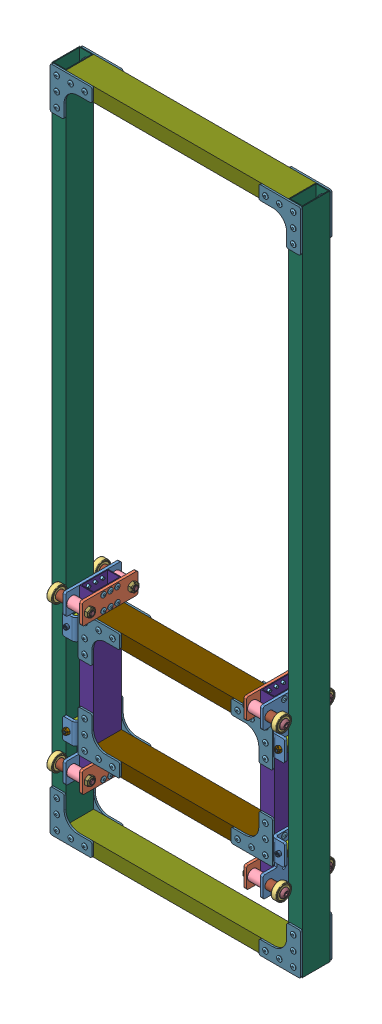
SolidWorks assembly am-3844a Example Single Stage Elevator Bearing Kit (1).STEP, configuration Default. Lengths in mm.
Overall size (457.2 1219.2 116.33).
248 component instances, 18 part files, 0 mates.
Components (placement in the parent):
- Example Single Corner Bearing Assembly R2.STEP-1: Example Single Corner Bearing Assembly R2.STEP [Default] at (14.8715 309.5253 9.4128) x (0 0 1) z (-1 0 0) size (112.43 88.9 74.91)
  - Large Bearing Block Plate R2.STEP-1: Large Bearing Block Plate R2.STEP [Default] at (-85.6128 70.3392 -35.9285) x (1 0 0) z (0 -1 0) size (101.6 24.99 88.9)
  - Small Bearing Block Plate R2.STEP-1: Small Bearing Block Plate R2.STEP [Default] at (-85.6128 70.3392 -66.091) x (1 0 0) z (0 -1 0) size (101.6 4.76 38.1)
  - 1614Z Bearing.STEP-1: 1614Z Bearing.STEP [Default] at (-74.6273 89.3892 -8.941) x (0.346238 -0.938147 0) z (0 0 1) size (28.57 28.57 9.53)
  - 1614Z Bearing.STEP-2: 1614Z Bearing.STEP [Default] at (5.0017 89.3892 -8.941) x (0.999932 0.011696 0) z (0 0 1) size (28.57 28.57 9.53)
  - AS75-18-64 Aluminum Spacer.STEP-1: AS75-18-64 Aluminum Spacer.STEP [Default] at (5.0017 89.3892 -35.9285) x (-0.078952 0.996878 0) z (-0.996878 -0.078952 0) size (19.05 25.4 19.05)
  - AS75-18-64 Aluminum Spacer.STEP-2: AS75-18-64 Aluminum Spacer.STEP [Default] at (-74.6273 89.3892 -61.3285) x (-0.205985 0.978555 0) z (0.978555 0.205985 0) size (19.05 25.4 19.05)
  - 187 pop rivet.STEP-1: 187 pop rivet.STEP [Default] at (-22.1128 102.0892 -41.707) x (0.970848 -0.239695 0) z (-0.239695 -0.970848 0) size (9.53 12.06 9.53)
  - 187 pop rivet.STEP-2: 187 pop rivet.STEP [Default] at (-22.1128 102.0892 -55.55) x (1 0 0) z (0 1 0) size (9.53 12.06 9.53)
  - 187 pop rivet.STEP-3: 187 pop rivet.STEP [Default] at (-34.8128 102.0892 -41.707) x (0.970848 -0.239695 0) z (-0.239695 -0.970848 0) size (9.53 12.06 9.53)
  - 187 pop rivet.STEP-4: 187 pop rivet.STEP [Default] at (-47.5128 102.0892 -41.707) x (0.970848 -0.239695 0) z (-0.239695 -0.970848 0) size (9.53 12.06 9.53)
  - 187 pop rivet.STEP-5: 187 pop rivet.STEP [Default] at (-22.1128 25.8892 -41.707) x (0.970848 -0.239695 0) z (-0.239695 -0.970848 0) size (9.53 12.06 9.53)
  - 187 pop rivet.STEP-6: 187 pop rivet.STEP [Default] at (-34.8128 25.8892 -41.707) x (0.970848 -0.239695 0) z (-0.239695 -0.970848 0) size (9.53 12.06 9.53)
  - 187 pop rivet.STEP-7: 187 pop rivet.STEP [Default] at (-47.5128 25.8892 -41.707) x (0.970848 -0.239695 0) z (-0.239695 -0.970848 0) size (9.53 12.06 9.53)
  - 187 pop rivet.STEP-8: 187 pop rivet.STEP [Default] at (-22.1128 76.6892 -55.55) x (1 0 0) z (0 1 0) size (9.53 12.06 9.53)
  - 187 pop rivet.STEP-9: 187 pop rivet.STEP [Default] at (-34.8128 102.0892 -55.55) x (1 0 0) z (0 1 0) size (9.53 12.06 9.53)
  - 187 pop rivet.STEP-10: 187 pop rivet.STEP [Default] at (-34.8128 76.6892 -55.55) x (1 0 0) z (0 1 0) size (9.53 12.06 9.53)
  - 187 pop rivet.STEP-11: 187 pop rivet.STEP [Default] at (-47.5128 102.0892 -55.55) x (1 0 0) z (0 1 0) size (9.53 12.06 9.53)
  - 187 pop rivet.STEP-12: 187 pop rivet.STEP [Default] at (-47.5128 76.6892 -55.55) x (1 0 0) z (0 1 0) size (9.53 12.06 9.53)
  - am-0602 .250 x .192 x 2.14 Brass Tube.STEP-1: am-0602 .250 x .192 x 2.14 Brass Tube.STEP [Default] at (-7.6348 38.5892 -20.0535) x (0 -0.358682 0.93346) z (-1 0 0) size (6.35 6.35 54.36)
  - 13RS075051 .750 x .260 x 1.00 Spacer.STEP-1: 13RS075051 .750 x .260 x 1.00 Spacer.STEP [Default] at (-60.2128 38.5892 -20.0535) x (0 -0.722855 0.691) z (0 0.691 0.722855) size (19.05 25.4 19.05)
  - 13RS075051 .750 x .260 x 1.00 Spacer.STEP-2: 13RS075051 .750 x .260 x 1.00 Spacer.STEP [Default] at (-34.8128 38.5892 -20.0535) x (0 -0.801304 -0.598258) z (0 -0.598258 0.801304) size (19.05 25.4 19.05)
  - 0.25 Flat Washer_Preferred Wide FW 0.25.STEP-1: 0.25 Flat Washer_Preferred Wide FW 0.25.STEP [Default] at (-60.2128 38.5892 -20.0535) x (1 0 0) z (0 -0.116572 0.993182) size (1.4 15.88 15.88)
  - 0.25 Flat Washer_Preferred Wide FW 0.25.STEP-2: 0.25 Flat Washer_Preferred Wide FW 0.25.STEP [Default] at (-8.0158 38.5892 -20.0535) size (1.4 15.88 15.88)
  - 10-32 Nylock Nut.STEP-1: 10-32 Nylock Nut.STEP [Default] at (-66.7533 38.5892 -20.0535) x (0 -0.097883 0.995198) z (-1 0 0) size (9.53 11.17 7.11)
  - SHCS 10-32 x 2.75_HX-SHCS 0.19-32x2.75x0.875-C.STEP-1: SHCS 10-32 x 2.75_HX-SHCS 0.19-32x2.75x0.875-C.STEP [Default] at (1.9537 38.5892 -20.0535) x (-1 0 0) z (0 -0.944703 0.327928) size (74.68 7.94 7.94)
  - AS62-18-44 Aluminum Spacer.STEP-1: AS62-18-44 Aluminum Spacer.STEP [Default] at (5.0017 89.3892 -13.7035) x (0.999229 -0.039261 0) z (0.039261 0.999229 0) size (15.88 17.46 15.88)
  - AS62-18-44 Aluminum Spacer.STEP-2: AS62-18-44 Aluminum Spacer.STEP [Default] at (-74.6273 89.3892 -13.7035) x (1 0 0) z (0 1 0) size (15.88 17.46 15.88)
  - 38-16 Nylock Jam Nut_90566A031.STEP-1: 38-16 Nylock Jam Nut_90566A031.STEP [Default] at (5.0017 89.3892 -66.091) x (1 0 0) z (0 1 0) size (14.29 6.75 16.5)
  - 38-16 Nylock Jam Nut_90566A031.STEP-2: 38-16 Nylock Jam Nut_90566A031.STEP [Default] at (-74.6273 89.3892 -66.091) x (1 0 0) z (0 1 0) size (14.29 6.75 16.5)
  - 91255A636_ALLOY STEEL BUTTON-HEAD SOCKET CAP SCREW_91255A636.STEP-1: 91255A636_ALLOY STEEL BUTTON-HEAD SOCKET CAP SCREW_91255A636.STEP [Default] at (-74.6273 89.3892 0.8761) size (16.66 16.66 74.91)
  - 91255A636_ALLOY STEEL BUTTON-HEAD SOCKET CAP SCREW_91255A636.STEP-2: 91255A636_ALLOY STEEL BUTTON-HEAD SOCKET CAP SCREW_91255A636.STEP [Default] at (5.0017 89.3892 0.8761) size (16.66 16.66 74.91)
- Example Single Corner Bearing Assembly R2.STEP-2: Example Single Corner Bearing Assembly R2.STEP [Default] at (14.8715 221.6036 -60.2128) x (0 0 -1) z (-1 0 0) size (112.43 88.9 74.91)
  - Large Bearing Block Plate R2.STEP-1: Large Bearing Block Plate R2.STEP [Default] at (-85.6128 70.3392 -35.9285) x (1 0 0) z (0 -1 0) size (101.6 24.99 88.9)
  - Small Bearing Block Plate R2.STEP-1: Small Bearing Block Plate R2.STEP [Default] at (-85.6128 70.3392 -66.091) x (1 0 0) z (0 -1 0) size (101.6 4.76 38.1)
  - 1614Z Bearing.STEP-1: 1614Z Bearing.STEP [Default] at (-74.6273 89.3892 -8.941) x (0.346238 -0.938147 0) z (0 0 1) size (28.57 28.57 9.53)
  - 1614Z Bearing.STEP-2: 1614Z Bearing.STEP [Default] at (5.0017 89.3892 -8.941) x (0.999932 0.011696 0) z (0 0 1) size (28.57 28.57 9.53)
  - AS75-18-64 Aluminum Spacer.STEP-1: AS75-18-64 Aluminum Spacer.STEP [Default] at (5.0017 89.3892 -35.9285) x (-0.078952 0.996878 0) z (-0.996878 -0.078952 0) size (19.05 25.4 19.05)
  - AS75-18-64 Aluminum Spacer.STEP-2: AS75-18-64 Aluminum Spacer.STEP [Default] at (-74.6273 89.3892 -61.3285) x (-0.205985 0.978555 0) z (0.978555 0.205985 0) size (19.05 25.4 19.05)
  - 187 pop rivet.STEP-1: 187 pop rivet.STEP [Default] at (-22.1128 102.0892 -41.707) x (0.970848 -0.239695 0) z (-0.239695 -0.970848 0) size (9.53 12.06 9.53)
  - 187 pop rivet.STEP-2: 187 pop rivet.STEP [Default] at (-22.1128 102.0892 -55.55) x (1 0 0) z (0 1 0) size (9.53 12.06 9.53)
  - 187 pop rivet.STEP-3: 187 pop rivet.STEP [Default] at (-34.8128 102.0892 -41.707) x (0.970848 -0.239695 0) z (-0.239695 -0.970848 0) size (9.53 12.06 9.53)
  - 187 pop rivet.STEP-4: 187 pop rivet.STEP [Default] at (-47.5128 102.0892 -41.707) x (0.970848 -0.239695 0) z (-0.239695 -0.970848 0) size (9.53 12.06 9.53)
  - 187 pop rivet.STEP-5: 187 pop rivet.STEP [Default] at (-22.1128 25.8892 -41.707) x (0.970848 -0.239695 0) z (-0.239695 -0.970848 0) size (9.53 12.06 9.53)
  - 187 pop rivet.STEP-6: 187 pop rivet.STEP [Default] at (-34.8128 25.8892 -41.707) x (0.970848 -0.239695 0) z (-0.239695 -0.970848 0) size (9.53 12.06 9.53)
  - 187 pop rivet.STEP-7: 187 pop rivet.STEP [Default] at (-47.5128 25.8892 -41.707) x (0.970848 -0.239695 0) z (-0.239695 -0.970848 0) size (9.53 12.06 9.53)
  - 187 pop rivet.STEP-8: 187 pop rivet.STEP [Default] at (-22.1128 76.6892 -55.55) x (1 0 0) z (0 1 0) size (9.53 12.06 9.53)
  - 187 pop rivet.STEP-9: 187 pop rivet.STEP [Default] at (-34.8128 102.0892 -55.55) x (1 0 0) z (0 1 0) size (9.53 12.06 9.53)
  - 187 pop rivet.STEP-10: 187 pop rivet.STEP [Default] at (-34.8128 76.6892 -55.55) x (1 0 0) z (0 1 0) size (9.53 12.06 9.53)
  - 187 pop rivet.STEP-11: 187 pop rivet.STEP [Default] at (-47.5128 102.0892 -55.55) x (1 0 0) z (0 1 0) size (9.53 12.06 9.53)
  - 187 pop rivet.STEP-12: 187 pop rivet.STEP [Default] at (-47.5128 76.6892 -55.55) x (1 0 0) z (0 1 0) size (9.53 12.06 9.53)
  - am-0602 .250 x .192 x 2.14 Brass Tube.STEP-1: am-0602 .250 x .192 x 2.14 Brass Tube.STEP [Default] at (-7.6348 38.5892 -20.0535) x (0 -0.358682 0.93346) z (-1 0 0) size (6.35 6.35 54.36)
  - 13RS075051 .750 x .260 x 1.00 Spacer.STEP-1: 13RS075051 .750 x .260 x 1.00 Spacer.STEP [Default] at (-60.2128 38.5892 -20.0535) x (0 -0.722855 0.691) z (0 0.691 0.722855) size (19.05 25.4 19.05)
  - 13RS075051 .750 x .260 x 1.00 Spacer.STEP-2: 13RS075051 .750 x .260 x 1.00 Spacer.STEP [Default] at (-34.8128 38.5892 -20.0535) x (0 -0.801304 -0.598258) z (0 -0.598258 0.801304) size (19.05 25.4 19.05)
  - 0.25 Flat Washer_Preferred Wide FW 0.25.STEP-1: 0.25 Flat Washer_Preferred Wide FW 0.25.STEP [Default] at (-60.2128 38.5892 -20.0535) x (1 0 0) z (0 -0.116572 0.993182) size (1.4 15.88 15.88)
  - 0.25 Flat Washer_Preferred Wide FW 0.25.STEP-2: 0.25 Flat Washer_Preferred Wide FW 0.25.STEP [Default] at (-8.0158 38.5892 -20.0535) size (1.4 15.88 15.88)
  - 10-32 Nylock Nut.STEP-1: 10-32 Nylock Nut.STEP [Default] at (-66.7533 38.5892 -20.0535) x (0 -0.097883 0.995198) z (-1 0 0) size (9.53 11.17 7.11)
  - SHCS 10-32 x 2.75_HX-SHCS 0.19-32x2.75x0.875-C.STEP-1: SHCS 10-32 x 2.75_HX-SHCS 0.19-32x2.75x0.875-C.STEP [Default] at (1.9537 38.5892 -20.0535) x (-1 0 0) z (0 -0.944703 0.327928) size (74.68 7.94 7.94)
  - AS62-18-44 Aluminum Spacer.STEP-1: AS62-18-44 Aluminum Spacer.STEP [Default] at (5.0017 89.3892 -13.7035) x (0.999229 -0.039261 0) z (0.039261 0.999229 0) size (15.88 17.46 15.88)
  - AS62-18-44 Aluminum Spacer.STEP-2: AS62-18-44 Aluminum Spacer.STEP [Default] at (-74.6273 89.3892 -13.7035) x (1 0 0) z (0 1 0) size (15.88 17.46 15.88)
  - 38-16 Nylock Jam Nut_90566A031.STEP-1: 38-16 Nylock Jam Nut_90566A031.STEP [Default] at (5.0017 89.3892 -66.091) x (1 0 0) z (0 1 0) size (14.29 6.75 16.5)
  - 38-16 Nylock Jam Nut_90566A031.STEP-2: 38-16 Nylock Jam Nut_90566A031.STEP [Default] at (-74.6273 89.3892 -66.091) x (1 0 0) z (0 1 0) size (14.29 6.75 16.5)
  - 91255A636_ALLOY STEEL BUTTON-HEAD SOCKET CAP SCREW_91255A636.STEP-1: 91255A636_ALLOY STEEL BUTTON-HEAD SOCKET CAP SCREW_91255A636.STEP [Default] at (-74.6273 89.3892 0.8761) size (16.66 16.66 74.91)
  - 91255A636_ALLOY STEEL BUTTON-HEAD SOCKET CAP SCREW_91255A636.STEP-2: 91255A636_ALLOY STEEL BUTTON-HEAD SOCKET CAP SCREW_91255A636.STEP [Default] at (5.0017 89.3892 0.8761) size (16.66 16.66 74.91)
- Example Single Corner Bearing Assembly R2.STEP-3: Example Single Corner Bearing Assembly R2.STEP [Default] at (442.3285 309.5253 -60.2128) x (0 0 -1) z (1 0 0) size (112.43 88.9 74.91)
  - Large Bearing Block Plate R2.STEP-1: Large Bearing Block Plate R2.STEP [Default] at (-85.6128 70.3392 -35.9285) x (1 0 0) z (0 -1 0) size (101.6 24.99 88.9)
  - Small Bearing Block Plate R2.STEP-1: Small Bearing Block Plate R2.STEP [Default] at (-85.6128 70.3392 -66.091) x (1 0 0) z (0 -1 0) size (101.6 4.76 38.1)
  - 1614Z Bearing.STEP-1: 1614Z Bearing.STEP [Default] at (-74.6273 89.3892 -8.941) x (0.346238 -0.938147 0) z (0 0 1) size (28.57 28.57 9.53)
  - 1614Z Bearing.STEP-2: 1614Z Bearing.STEP [Default] at (5.0017 89.3892 -8.941) x (0.999932 0.011696 0) z (0 0 1) size (28.57 28.57 9.53)
  - AS75-18-64 Aluminum Spacer.STEP-1: AS75-18-64 Aluminum Spacer.STEP [Default] at (5.0017 89.3892 -35.9285) x (-0.078952 0.996878 0) z (-0.996878 -0.078952 0) size (19.05 25.4 19.05)
  - AS75-18-64 Aluminum Spacer.STEP-2: AS75-18-64 Aluminum Spacer.STEP [Default] at (-74.6273 89.3892 -61.3285) x (-0.205985 0.978555 0) z (0.978555 0.205985 0) size (19.05 25.4 19.05)
  - 187 pop rivet.STEP-1: 187 pop rivet.STEP [Default] at (-22.1128 102.0892 -41.707) x (0.970848 -0.239695 0) z (-0.239695 -0.970848 0) size (9.53 12.06 9.53)
  - 187 pop rivet.STEP-2: 187 pop rivet.STEP [Default] at (-22.1128 102.0892 -55.55) x (1 0 0) z (0 1 0) size (9.53 12.06 9.53)
  - 187 pop rivet.STEP-3: 187 pop rivet.STEP [Default] at (-34.8128 102.0892 -41.707) x (0.970848 -0.239695 0) z (-0.239695 -0.970848 0) size (9.53 12.06 9.53)
  - 187 pop rivet.STEP-4: 187 pop rivet.STEP [Default] at (-47.5128 102.0892 -41.707) x (0.970848 -0.239695 0) z (-0.239695 -0.970848 0) size (9.53 12.06 9.53)
  - 187 pop rivet.STEP-5: 187 pop rivet.STEP [Default] at (-22.1128 25.8892 -41.707) x (0.970848 -0.239695 0) z (-0.239695 -0.970848 0) size (9.53 12.06 9.53)
  - 187 pop rivet.STEP-6: 187 pop rivet.STEP [Default] at (-34.8128 25.8892 -41.707) x (0.970848 -0.239695 0) z (-0.239695 -0.970848 0) size (9.53 12.06 9.53)
  - 187 pop rivet.STEP-7: 187 pop rivet.STEP [Default] at (-47.5128 25.8892 -41.707) x (0.970848 -0.239695 0) z (-0.239695 -0.970848 0) size (9.53 12.06 9.53)
  - 187 pop rivet.STEP-8: 187 pop rivet.STEP [Default] at (-22.1128 76.6892 -55.55) x (1 0 0) z (0 1 0) size (9.53 12.06 9.53)
  - 187 pop rivet.STEP-9: 187 pop rivet.STEP [Default] at (-34.8128 102.0892 -55.55) x (1 0 0) z (0 1 0) size (9.53 12.06 9.53)
  - 187 pop rivet.STEP-10: 187 pop rivet.STEP [Default] at (-34.8128 76.6892 -55.55) x (1 0 0) z (0 1 0) size (9.53 12.06 9.53)
  - 187 pop rivet.STEP-11: 187 pop rivet.STEP [Default] at (-47.5128 102.0892 -55.55) x (1 0 0) z (0 1 0) size (9.53 12.06 9.53)
  - 187 pop rivet.STEP-12: 187 pop rivet.STEP [Default] at (-47.5128 76.6892 -55.55) x (1 0 0) z (0 1 0) size (9.53 12.06 9.53)
  - am-0602 .250 x .192 x 2.14 Brass Tube.STEP-1: am-0602 .250 x .192 x 2.14 Brass Tube.STEP [Default] at (-7.6348 38.5892 -20.0535) x (0 -0.358682 0.93346) z (-1 0 0) size (6.35 6.35 54.36)
  - 13RS075051 .750 x .260 x 1.00 Spacer.STEP-1: 13RS075051 .750 x .260 x 1.00 Spacer.STEP [Default] at (-60.2128 38.5892 -20.0535) x (0 -0.722855 0.691) z (0 0.691 0.722855) size (19.05 25.4 19.05)
  - 13RS075051 .750 x .260 x 1.00 Spacer.STEP-2: 13RS075051 .750 x .260 x 1.00 Spacer.STEP [Default] at (-34.8128 38.5892 -20.0535) x (0 -0.801304 -0.598258) z (0 -0.598258 0.801304) size (19.05 25.4 19.05)
  - 0.25 Flat Washer_Preferred Wide FW 0.25.STEP-1: 0.25 Flat Washer_Preferred Wide FW 0.25.STEP [Default] at (-60.2128 38.5892 -20.0535) x (1 0 0) z (0 -0.116572 0.993182) size (1.4 15.88 15.88)
  - 0.25 Flat Washer_Preferred Wide FW 0.25.STEP-2: 0.25 Flat Washer_Preferred Wide FW 0.25.STEP [Default] at (-8.0158 38.5892 -20.0535) size (1.4 15.88 15.88)
  - 10-32 Nylock Nut.STEP-1: 10-32 Nylock Nut.STEP [Default] at (-66.7533 38.5892 -20.0535) x (0 -0.097883 0.995198) z (-1 0 0) size (9.53 11.17 7.11)
  - SHCS 10-32 x 2.75_HX-SHCS 0.19-32x2.75x0.875-C.STEP-1: SHCS 10-32 x 2.75_HX-SHCS 0.19-32x2.75x0.875-C.STEP [Default] at (1.9537 38.5892 -20.0535) x (-1 0 0) z (0 -0.944703 0.327928) size (74.68 7.94 7.94)
  - AS62-18-44 Aluminum Spacer.STEP-1: AS62-18-44 Aluminum Spacer.STEP [Default] at (5.0017 89.3892 -13.7035) x (0.999229 -0.039261 0) z (0.039261 0.999229 0) size (15.88 17.46 15.88)
  - AS62-18-44 Aluminum Spacer.STEP-2: AS62-18-44 Aluminum Spacer.STEP [Default] at (-74.6273 89.3892 -13.7035) x (1 0 0) z (0 1 0) size (15.88 17.46 15.88)
  - 38-16 Nylock Jam Nut_90566A031.STEP-1: 38-16 Nylock Jam Nut_90566A031.STEP [Default] at (5.0017 89.3892 -66.091) x (1 0 0) z (0 1 0) size (14.29 6.75 16.5)
  - 38-16 Nylock Jam Nut_90566A031.STEP-2: 38-16 Nylock Jam Nut_90566A031.STEP [Default] at (-74.6273 89.3892 -66.091) x (1 0 0) z (0 1 0) size (14.29 6.75 16.5)
  - 91255A636_ALLOY STEEL BUTTON-HEAD SOCKET CAP SCREW_91255A636.STEP-1: 91255A636_ALLOY STEEL BUTTON-HEAD SOCKET CAP SCREW_91255A636.STEP [Default] at (-74.6273 89.3892 0.8761) size (16.66 16.66 74.91)
  - 91255A636_ALLOY STEEL BUTTON-HEAD SOCKET CAP SCREW_91255A636.STEP-2: 91255A636_ALLOY STEEL BUTTON-HEAD SOCKET CAP SCREW_91255A636.STEP [Default] at (5.0017 89.3892 0.8761) size (16.66 16.66 74.91)
- Example Single Corner Bearing Assembly R2.STEP-4: Example Single Corner Bearing Assembly R2.STEP [Default] at (442.3285 221.6036 9.4128) x (0 0 1) z (1 0 0) size (112.43 88.9 74.91)
  - Large Bearing Block Plate R2.STEP-1: Large Bearing Block Plate R2.STEP [Default] at (-85.6128 70.3392 -35.9285) x (1 0 0) z (0 -1 0) size (101.6 24.99 88.9)
  - Small Bearing Block Plate R2.STEP-1: Small Bearing Block Plate R2.STEP [Default] at (-85.6128 70.3392 -66.091) x (1 0 0) z (0 -1 0) size (101.6 4.76 38.1)
  - 1614Z Bearing.STEP-1: 1614Z Bearing.STEP [Default] at (-74.6273 89.3892 -8.941) x (0.346238 -0.938147 0) z (0 0 1) size (28.57 28.57 9.53)
  - 1614Z Bearing.STEP-2: 1614Z Bearing.STEP [Default] at (5.0017 89.3892 -8.941) x (0.999932 0.011696 0) z (0 0 1) size (28.57 28.57 9.53)
  - AS75-18-64 Aluminum Spacer.STEP-1: AS75-18-64 Aluminum Spacer.STEP [Default] at (5.0017 89.3892 -35.9285) x (-0.078952 0.996878 0) z (-0.996878 -0.078952 0) size (19.05 25.4 19.05)
  - AS75-18-64 Aluminum Spacer.STEP-2: AS75-18-64 Aluminum Spacer.STEP [Default] at (-74.6273 89.3892 -61.3285) x (-0.205985 0.978555 0) z (0.978555 0.205985 0) size (19.05 25.4 19.05)
  - 187 pop rivet.STEP-1: 187 pop rivet.STEP [Default] at (-22.1128 102.0892 -41.707) x (0.970848 -0.239695 0) z (-0.239695 -0.970848 0) size (9.53 12.06 9.53)
  - 187 pop rivet.STEP-2: 187 pop rivet.STEP [Default] at (-22.1128 102.0892 -55.55) x (1 0 0) z (0 1 0) size (9.53 12.06 9.53)
  - 187 pop rivet.STEP-3: 187 pop rivet.STEP [Default] at (-34.8128 102.0892 -41.707) x (0.970848 -0.239695 0) z (-0.239695 -0.970848 0) size (9.53 12.06 9.53)
  - 187 pop rivet.STEP-4: 187 pop rivet.STEP [Default] at (-47.5128 102.0892 -41.707) x (0.970848 -0.239695 0) z (-0.239695 -0.970848 0) size (9.53 12.06 9.53)
  - 187 pop rivet.STEP-5: 187 pop rivet.STEP [Default] at (-22.1128 25.8892 -41.707) x (0.970848 -0.239695 0) z (-0.239695 -0.970848 0) size (9.53 12.06 9.53)
  - 187 pop rivet.STEP-6: 187 pop rivet.STEP [Default] at (-34.8128 25.8892 -41.707) x (0.970848 -0.239695 0) z (-0.239695 -0.970848 0) size (9.53 12.06 9.53)
  - 187 pop rivet.STEP-7: 187 pop rivet.STEP [Default] at (-47.5128 25.8892 -41.707) x (0.970848 -0.239695 0) z (-0.239695 -0.970848 0) size (9.53 12.06 9.53)
  - 187 pop rivet.STEP-8: 187 pop rivet.STEP [Default] at (-22.1128 76.6892 -55.55) x (1 0 0) z (0 1 0) size (9.53 12.06 9.53)
  - 187 pop rivet.STEP-9: 187 pop rivet.STEP [Default] at (-34.8128 102.0892 -55.55) x (1 0 0) z (0 1 0) size (9.53 12.06 9.53)
  - 187 pop rivet.STEP-10: 187 pop rivet.STEP [Default] at (-34.8128 76.6892 -55.55) x (1 0 0) z (0 1 0) size (9.53 12.06 9.53)
  - 187 pop rivet.STEP-11: 187 pop rivet.STEP [Default] at (-47.5128 102.0892 -55.55) x (1 0 0) z (0 1 0) size (9.53 12.06 9.53)
  - 187 pop rivet.STEP-12: 187 pop rivet.STEP [Default] at (-47.5128 76.6892 -55.55) x (1 0 0) z (0 1 0) size (9.53 12.06 9.53)
  - am-0602 .250 x .192 x 2.14 Brass Tube.STEP-1: am-0602 .250 x .192 x 2.14 Brass Tube.STEP [Default] at (-7.6348 38.5892 -20.0535) x (0 -0.358682 0.93346) z (-1 0 0) size (6.35 6.35 54.36)
  - 13RS075051 .750 x .260 x 1.00 Spacer.STEP-1: 13RS075051 .750 x .260 x 1.00 Spacer.STEP [Default] at (-60.2128 38.5892 -20.0535) x (0 -0.722855 0.691) z (0 0.691 0.722855) size (19.05 25.4 19.05)
  - 13RS075051 .750 x .260 x 1.00 Spacer.STEP-2: 13RS075051 .750 x .260 x 1.00 Spacer.STEP [Default] at (-34.8128 38.5892 -20.0535) x (0 -0.801304 -0.598258) z (0 -0.598258 0.801304) size (19.05 25.4 19.05)
  - 0.25 Flat Washer_Preferred Wide FW 0.25.STEP-1: 0.25 Flat Washer_Preferred Wide FW 0.25.STEP [Default] at (-60.2128 38.5892 -20.0535) x (1 0 0) z (0 -0.116572 0.993182) size (1.4 15.88 15.88)
  - 0.25 Flat Washer_Preferred Wide FW 0.25.STEP-2: 0.25 Flat Washer_Preferred Wide FW 0.25.STEP [Default] at (-8.0158 38.5892 -20.0535) size (1.4 15.88 15.88)
  - 10-32 Nylock Nut.STEP-1: 10-32 Nylock Nut.STEP [Default] at (-66.7533 38.5892 -20.0535) x (0 -0.097883 0.995198) z (-1 0 0) size (9.53 11.17 7.11)
  - SHCS 10-32 x 2.75_HX-SHCS 0.19-32x2.75x0.875-C.STEP-1: SHCS 10-32 x 2.75_HX-SHCS 0.19-32x2.75x0.875-C.STEP [Default] at (1.9537 38.5892 -20.0535) x (-1 0 0) z (0 -0.944703 0.327928) size (74.68 7.94 7.94)
  - AS62-18-44 Aluminum Spacer.STEP-1: AS62-18-44 Aluminum Spacer.STEP [Default] at (5.0017 89.3892 -13.7035) x (0.999229 -0.039261 0) z (0.039261 0.999229 0) size (15.88 17.46 15.88)
  - AS62-18-44 Aluminum Spacer.STEP-2: AS62-18-44 Aluminum Spacer.STEP [Default] at (-74.6273 89.3892 -13.7035) x (1 0 0) z (0 1 0) size (15.88 17.46 15.88)
  - 38-16 Nylock Jam Nut_90566A031.STEP-1: 38-16 Nylock Jam Nut_90566A031.STEP [Default] at (5.0017 89.3892 -66.091) x (1 0 0) z (0 1 0) size (14.29 6.75 16.5)
  - 38-16 Nylock Jam Nut_90566A031.STEP-2: 38-16 Nylock Jam Nut_90566A031.STEP [Default] at (-74.6273 89.3892 -66.091) x (1 0 0) z (0 1 0) size (14.29 6.75 16.5)
  - 91255A636_ALLOY STEEL BUTTON-HEAD SOCKET CAP SCREW_91255A636.STEP-1: 91255A636_ALLOY STEEL BUTTON-HEAD SOCKET CAP SCREW_91255A636.STEP [Default] at (-74.6273 89.3892 0.8761) size (16.66 16.66 74.91)
  - 91255A636_ALLOY STEEL BUTTON-HEAD SOCKET CAP SCREW_91255A636.STEP-2: 91255A636_ALLOY STEEL BUTTON-HEAD SOCKET CAP SCREW_91255A636.STEP [Default] at (5.0017 89.3892 0.8761) size (16.66 16.66 74.91)
- am-3860 90 Gusset with Rivets.STEP-1: am-3860 90 Gusset with Rivets.STEP [Default] at (379.0872 1079.1222 -32.0758) x (0 -1 0) z (1 0 0) size (76.2 12.06 76.2)
  - am-3860 90 Gusset.STEP-1: am-3860 90 Gusset.STEP [Default] at (-140.0778 18.7242 78.1128) size (76.2 3.17 76.2)
  - 187 pop rivet.STEP-1: 187 pop rivet.STEP [Default] at (-127.3778 11.3582 65.4128) size (9.53 12.06 9.53)
  - 187 pop rivet.STEP-2: 187 pop rivet.STEP [Default] at (-101.9778 11.3582 65.4128) size (9.53 12.06 9.53)
  - 187 pop rivet.STEP-3: 187 pop rivet.STEP [Default] at (-76.5778 11.3582 65.4128) size (9.53 12.06 9.53)
  - 187 pop rivet.STEP-4: 187 pop rivet.STEP [Default] at (-127.3778 11.3582 40.0128) size (9.53 12.06 9.53)
  - 187 pop rivet.STEP-5: 187 pop rivet.STEP [Default] at (-127.3778 11.3582 14.6128) size (9.53 12.06 9.53)
- am-3860 90 Gusset with Rivets.STEP-2: am-3860 90 Gusset with Rivets.STEP [Default] at (317.1222 1141.0872 -18.7242) x (-1 0 0) z (0 1 0) size (76.2 12.06 76.2)
  - am-3860 90 Gusset.STEP-1: am-3860 90 Gusset.STEP [Default] at (-140.0778 18.7242 78.1128) size (76.2 3.17 76.2)
  - 187 pop rivet.STEP-1: 187 pop rivet.STEP [Default] at (-127.3778 11.3582 65.4128) size (9.53 12.06 9.53)
  - 187 pop rivet.STEP-2: 187 pop rivet.STEP [Default] at (-101.9778 11.3582 65.4128) size (9.53 12.06 9.53)
  - 187 pop rivet.STEP-3: 187 pop rivet.STEP [Default] at (-76.5778 11.3582 65.4128) size (9.53 12.06 9.53)
  - 187 pop rivet.STEP-4: 187 pop rivet.STEP [Default] at (-127.3778 11.3582 40.0128) size (9.53 12.06 9.53)
  - 187 pop rivet.STEP-5: 187 pop rivet.STEP [Default] at (-127.3778 11.3582 14.6128) size (9.53 12.06 9.53)
- am-3860 90 Gusset with Rivets.STEP-3: am-3860 90 Gusset with Rivets.STEP [Default] at (78.1128 1079.1222 -18.7242) x (0 -1 0) z (-1 0 0) size (76.2 12.06 76.2)
  - am-3860 90 Gusset.STEP-1: am-3860 90 Gusset.STEP [Default] at (-140.0778 18.7242 78.1128) size (76.2 3.17 76.2)
  - 187 pop rivet.STEP-1: 187 pop rivet.STEP [Default] at (-127.3778 11.3582 65.4128) size (9.53 12.06 9.53)
  - 187 pop rivet.STEP-2: 187 pop rivet.STEP [Default] at (-101.9778 11.3582 65.4128) size (9.53 12.06 9.53)
  - 187 pop rivet.STEP-3: 187 pop rivet.STEP [Default] at (-76.5778 11.3582 65.4128) size (9.53 12.06 9.53)
  - 187 pop rivet.STEP-4: 187 pop rivet.STEP [Default] at (-127.3778 11.3582 40.0128) size (9.53 12.06 9.53)
  - 187 pop rivet.STEP-5: 187 pop rivet.STEP [Default] at (-127.3778 11.3582 14.6128) size (9.53 12.06 9.53)
- am-3860 90 Gusset with Rivets.STEP-4: am-3860 90 Gusset with Rivets.STEP [Default] at (140.0778 1141.0872 -32.0758) x (1 0 0) z (0 1 0) size (76.2 12.06 76.2)
  - am-3860 90 Gusset.STEP-1: am-3860 90 Gusset.STEP [Default] at (-140.0778 18.7242 78.1128) size (76.2 3.17 76.2)
  - 187 pop rivet.STEP-1: 187 pop rivet.STEP [Default] at (-127.3778 11.3582 65.4128) size (9.53 12.06 9.53)
  - 187 pop rivet.STEP-2: 187 pop rivet.STEP [Default] at (-101.9778 11.3582 65.4128) size (9.53 12.06 9.53)
  - 187 pop rivet.STEP-3: 187 pop rivet.STEP [Default] at (-76.5778 11.3582 65.4128) size (9.53 12.06 9.53)
  - 187 pop rivet.STEP-4: 187 pop rivet.STEP [Default] at (-127.3778 11.3582 40.0128) size (9.53 12.06 9.53)
  - 187 pop rivet.STEP-5: 187 pop rivet.STEP [Default] at (-127.3778 11.3582 14.6128) size (9.53 12.06 9.53)
- am-3860 90 Gusset with Rivets.STEP-5: am-3860 90 Gusset with Rivets.STEP [Default] at (317.1222 78.1128 -32.0758) x (-1 0 0) z (0 -1 0) size (76.2 12.06 76.2)
  - am-3860 90 Gusset.STEP-1: am-3860 90 Gusset.STEP [Default] at (-140.0778 18.7242 78.1128) size (76.2 3.17 76.2)
  - 187 pop rivet.STEP-1: 187 pop rivet.STEP [Default] at (-127.3778 11.3582 65.4128) size (9.53 12.06 9.53)
  - 187 pop rivet.STEP-2: 187 pop rivet.STEP [Default] at (-101.9778 11.3582 65.4128) size (9.53 12.06 9.53)
  - 187 pop rivet.STEP-3: 187 pop rivet.STEP [Default] at (-76.5778 11.3582 65.4128) size (9.53 12.06 9.53)
  - 187 pop rivet.STEP-4: 187 pop rivet.STEP [Default] at (-127.3778 11.3582 40.0128) size (9.53 12.06 9.53)
  - 187 pop rivet.STEP-5: 187 pop rivet.STEP [Default] at (-127.3778 11.3582 14.6128) size (9.53 12.06 9.53)
- am-3860 90 Gusset with Rivets.STEP-6: am-3860 90 Gusset with Rivets.STEP [Default] at (379.0872 140.0778 -18.7242) x (0 1 0) z (1 0 0) size (76.2 12.06 76.2)
  - am-3860 90 Gusset.STEP-1: am-3860 90 Gusset.STEP [Default] at (-140.0778 18.7242 78.1128) size (76.2 3.17 76.2)
  - 187 pop rivet.STEP-1: 187 pop rivet.STEP [Default] at (-127.3778 11.3582 65.4128) size (9.53 12.06 9.53)
  - 187 pop rivet.STEP-2: 187 pop rivet.STEP [Default] at (-101.9778 11.3582 65.4128) size (9.53 12.06 9.53)
  - 187 pop rivet.STEP-3: 187 pop rivet.STEP [Default] at (-76.5778 11.3582 65.4128) size (9.53 12.06 9.53)
  - 187 pop rivet.STEP-4: 187 pop rivet.STEP [Default] at (-127.3778 11.3582 40.0128) size (9.53 12.06 9.53)
  - 187 pop rivet.STEP-5: 187 pop rivet.STEP [Default] at (-127.3778 11.3582 14.6128) size (9.53 12.06 9.53)
- am-3860 90 Gusset with Rivets.STEP-7: am-3860 90 Gusset with Rivets.STEP [Default] at (78.1128 140.0778 -32.0758) x (0 1 0) z (-1 0 0) size (76.2 12.06 76.2)
  - am-3860 90 Gusset.STEP-1: am-3860 90 Gusset.STEP [Default] at (-140.0778 18.7242 78.1128) size (76.2 3.17 76.2)
  - 187 pop rivet.STEP-1: 187 pop rivet.STEP [Default] at (-127.3778 11.3582 65.4128) size (9.53 12.06 9.53)
  - 187 pop rivet.STEP-2: 187 pop rivet.STEP [Default] at (-101.9778 11.3582 65.4128) size (9.53 12.06 9.53)
  - 187 pop rivet.STEP-3: 187 pop rivet.STEP [Default] at (-76.5778 11.3582 65.4128) size (9.53 12.06 9.53)
  - 187 pop rivet.STEP-4: 187 pop rivet.STEP [Default] at (-127.3778 11.3582 40.0128) size (9.53 12.06 9.53)
  - 187 pop rivet.STEP-5: 187 pop rivet.STEP [Default] at (-127.3778 11.3582 14.6128) size (9.53 12.06 9.53)
- am-3860 90 Gusset with Rivets.STEP-8: am-3860 90 Gusset with Rivets.STEP [Default] at (140.0778 78.1128 -18.7242) x (1 0 0) z (0 -1 0) size (76.2 12.06 76.2)
  - am-3860 90 Gusset.STEP-1: am-3860 90 Gusset.STEP [Default] at (-140.0778 18.7242 78.1128) size (76.2 3.17 76.2)
  - 187 pop rivet.STEP-1: 187 pop rivet.STEP [Default] at (-127.3778 11.3582 65.4128) size (9.53 12.06 9.53)
  - 187 pop rivet.STEP-2: 187 pop rivet.STEP [Default] at (-101.9778 11.3582 65.4128) size (9.53 12.06 9.53)
  - 187 pop rivet.STEP-3: 187 pop rivet.STEP [Default] at (-76.5778 11.3582 65.4128) size (9.53 12.06 9.53)
  - 187 pop rivet.STEP-4: 187 pop rivet.STEP [Default] at (-127.3778 11.3582 40.0128) size (9.53 12.06 9.53)
  - 187 pop rivet.STEP-5: 187 pop rivet.STEP [Default] at (-127.3778 11.3582 14.6128) size (9.53 12.06 9.53)
- am-3860 90 Gusset with Rivets.STEP-9: am-3860 90 Gusset with Rivets.STEP [Default] at (128.9128 291.3422 -32.0758) x (0 1 0) z (-1 0 0) size (76.2 12.06 76.2)
  - am-3860 90 Gusset.STEP-1: am-3860 90 Gusset.STEP [Default] at (-140.0778 18.7242 78.1128) size (76.2 3.17 76.2)
  - 187 pop rivet.STEP-1: 187 pop rivet.STEP [Default] at (-127.3778 11.3582 65.4128) size (9.53 12.06 9.53)
  - 187 pop rivet.STEP-2: 187 pop rivet.STEP [Default] at (-101.9778 11.3582 65.4128) size (9.53 12.06 9.53)
  - 187 pop rivet.STEP-3: 187 pop rivet.STEP [Default] at (-76.5778 11.3582 65.4128) size (9.53 12.06 9.53)
  - 187 pop rivet.STEP-4: 187 pop rivet.STEP [Default] at (-127.3778 11.3582 40.0128) size (9.53 12.06 9.53)
  - 187 pop rivet.STEP-5: 187 pop rivet.STEP [Default] at (-127.3778 11.3582 14.6128) size (9.53 12.06 9.53)
- am-3860 90 Gusset with Rivets.STEP-10: am-3860 90 Gusset with Rivets.STEP [Default] at (190.8778 229.3772 -18.7242) x (1 0 0) z (0 -1 0) size (76.2 12.06 76.2)
  - am-3860 90 Gusset.STEP-1: am-3860 90 Gusset.STEP [Default] at (-140.0778 18.7242 78.1128) size (76.2 3.17 76.2)
  - 187 pop rivet.STEP-1: 187 pop rivet.STEP [Default] at (-127.3778 11.3582 65.4128) size (9.53 12.06 9.53)
  - 187 pop rivet.STEP-2: 187 pop rivet.STEP [Default] at (-101.9778 11.3582 65.4128) size (9.53 12.06 9.53)
  - 187 pop rivet.STEP-3: 187 pop rivet.STEP [Default] at (-76.5778 11.3582 65.4128) size (9.53 12.06 9.53)
  - 187 pop rivet.STEP-4: 187 pop rivet.STEP [Default] at (-127.3778 11.3582 40.0128) size (9.53 12.06 9.53)
  - 187 pop rivet.STEP-5: 187 pop rivet.STEP [Default] at (-127.3778 11.3582 14.6128) size (9.53 12.06 9.53)
- am-3860 90 Gusset with Rivets.STEP-11: am-3860 90 Gusset with Rivets.STEP [Default] at (266.3222 229.3772 -32.0758) x (-1 0 0) z (0 -1 0) size (76.2 12.06 76.2)
  - am-3860 90 Gusset.STEP-1: am-3860 90 Gusset.STEP [Default] at (-140.0778 18.7242 78.1128) size (76.2 3.17 76.2)
  - 187 pop rivet.STEP-1: 187 pop rivet.STEP [Default] at (-127.3778 11.3582 65.4128) size (9.53 12.06 9.53)
  - 187 pop rivet.STEP-2: 187 pop rivet.STEP [Default] at (-101.9778 11.3582 65.4128) size (9.53 12.06 9.53)
  - 187 pop rivet.STEP-3: 187 pop rivet.STEP [Default] at (-76.5778 11.3582 65.4128) size (9.53 12.06 9.53)
  - 187 pop rivet.STEP-4: 187 pop rivet.STEP [Default] at (-127.3778 11.3582 40.0128) size (9.53 12.06 9.53)
  - 187 pop rivet.STEP-5: 187 pop rivet.STEP [Default] at (-127.3778 11.3582 14.6128) size (9.53 12.06 9.53)
- am-3860 90 Gusset with Rivets.STEP-12: am-3860 90 Gusset with Rivets.STEP [Default] at (328.2872 239.7867 -32.0758) x (0 -1 0) z (1 0 0) size (76.2 12.06 76.2)
  - am-3860 90 Gusset.STEP-1: am-3860 90 Gusset.STEP [Default] at (-140.0778 18.7242 78.1128) size (76.2 3.17 76.2)
  - 187 pop rivet.STEP-1: 187 pop rivet.STEP [Default] at (-127.3778 11.3582 65.4128) size (9.53 12.06 9.53)
  - 187 pop rivet.STEP-2: 187 pop rivet.STEP [Default] at (-101.9778 11.3582 65.4128) size (9.53 12.06 9.53)
  - 187 pop rivet.STEP-3: 187 pop rivet.STEP [Default] at (-76.5778 11.3582 65.4128) size (9.53 12.06 9.53)
  - 187 pop rivet.STEP-4: 187 pop rivet.STEP [Default] at (-127.3778 11.3582 40.0128) size (9.53 12.06 9.53)
  - 187 pop rivet.STEP-5: 187 pop rivet.STEP [Default] at (-127.3778 11.3582 14.6128) size (9.53 12.06 9.53)
- am-3860 90 Gusset with Rivets.STEP-13: am-3860 90 Gusset with Rivets.STEP [Default] at (128.9128 239.7867 -18.7242) x (0 -1 0) z (-1 0 0) size (76.2 12.06 76.2)
  - am-3860 90 Gusset.STEP-1: am-3860 90 Gusset.STEP [Default] at (-140.0778 18.7242 78.1128) size (76.2 3.17 76.2)
  - 187 pop rivet.STEP-1: 187 pop rivet.STEP [Default] at (-127.3778 11.3582 65.4128) size (9.53 12.06 9.53)
  - 187 pop rivet.STEP-2: 187 pop rivet.STEP [Default] at (-101.9778 11.3582 65.4128) size (9.53 12.06 9.53)
  - 187 pop rivet.STEP-3: 187 pop rivet.STEP [Default] at (-76.5778 11.3582 65.4128) size (9.53 12.06 9.53)
  - 187 pop rivet.STEP-4: 187 pop rivet.STEP [Default] at (-127.3778 11.3582 40.0128) size (9.53 12.06 9.53)
  - 187 pop rivet.STEP-5: 187 pop rivet.STEP [Default] at (-127.3778 11.3582 14.6128) size (9.53 12.06 9.53)
- am-3860 90 Gusset with Rivets.STEP-14: am-3860 90 Gusset with Rivets.STEP [Default] at (190.8778 301.7516 -32.0758) x (1 0 0) z (0 1 0) size (76.2 12.06 76.2)
  - am-3860 90 Gusset.STEP-1: am-3860 90 Gusset.STEP [Default] at (-140.0778 18.7242 78.1128) size (76.2 3.17 76.2)
  - 187 pop rivet.STEP-1: 187 pop rivet.STEP [Default] at (-127.3778 11.3582 65.4128) size (9.53 12.06 9.53)
  - 187 pop rivet.STEP-2: 187 pop rivet.STEP [Default] at (-101.9778 11.3582 65.4128) size (9.53 12.06 9.53)
  - 187 pop rivet.STEP-3: 187 pop rivet.STEP [Default] at (-76.5778 11.3582 65.4128) size (9.53 12.06 9.53)
  - 187 pop rivet.STEP-4: 187 pop rivet.STEP [Default] at (-127.3778 11.3582 40.0128) size (9.53 12.06 9.53)
  - 187 pop rivet.STEP-5: 187 pop rivet.STEP [Default] at (-127.3778 11.3582 14.6128) size (9.53 12.06 9.53)
- am-3860 90 Gusset with Rivets.STEP-15: am-3860 90 Gusset with Rivets.STEP [Default] at (266.3222 301.7516 -18.7242) x (-1 0 0) z (0 1 0) size (76.2 12.06 76.2)
  - am-3860 90 Gusset.STEP-1: am-3860 90 Gusset.STEP [Default] at (-140.0778 18.7242 78.1128) size (76.2 3.17 76.2)
  - 187 pop rivet.STEP-1: 187 pop rivet.STEP [Default] at (-127.3778 11.3582 65.4128) size (9.53 12.06 9.53)
  - 187 pop rivet.STEP-2: 187 pop rivet.STEP [Default] at (-101.9778 11.3582 65.4128) size (9.53 12.06 9.53)
  - 187 pop rivet.STEP-3: 187 pop rivet.STEP [Default] at (-76.5778 11.3582 65.4128) size (9.53 12.06 9.53)
  - 187 pop rivet.STEP-4: 187 pop rivet.STEP [Default] at (-127.3778 11.3582 40.0128) size (9.53 12.06 9.53)
  - 187 pop rivet.STEP-5: 187 pop rivet.STEP [Default] at (-127.3778 11.3582 14.6128) size (9.53 12.06 9.53)
- am-3860 90 Gusset with Rivets.STEP-16: am-3860 90 Gusset with Rivets.STEP [Default] at (328.2872 291.3422 -18.7242) x (0 1 0) z (1 0 0) size (76.2 12.06 76.2)
  - am-3860 90 Gusset.STEP-1: am-3860 90 Gusset.STEP [Default] at (-140.0778 18.7242 78.1128) size (76.2 3.17 76.2)
  - 187 pop rivet.STEP-1: 187 pop rivet.STEP [Default] at (-127.3778 11.3582 65.4128) size (9.53 12.06 9.53)
  - 187 pop rivet.STEP-2: 187 pop rivet.STEP [Default] at (-101.9778 11.3582 65.4128) size (9.53 12.06 9.53)
  - 187 pop rivet.STEP-3: 187 pop rivet.STEP [Default] at (-76.5778 11.3582 65.4128) size (9.53 12.06 9.53)
  - 187 pop rivet.STEP-4: 187 pop rivet.STEP [Default] at (-127.3778 11.3582 40.0128) size (9.53 12.06 9.53)
  - 187 pop rivet.STEP-5: 187 pop rivet.STEP [Default] at (-127.3778 11.3582 14.6128) size (9.53 12.06 9.53)
- Example Fixed Tube.STEP-1: Example Fixed Tube.STEP [Default] at (0 0 -50.8) x (0 0 1) z (-1 0 0) size (50.8 1219.2 25.4)
- Example Fixed Tube.STEP-2: Example Fixed Tube.STEP [Default] at (457.2 0 0) x (0 0 -1) z (1 0 0) size (50.8 1219.2 25.4)
- Example Cross Frame Tube.STEP-1: Example Cross Frame Tube.STEP [Default] at (431.8 1193.8 -50.8) x (0 0 1) z (0 -1 0) size (50.8 406.4 25.4)
- Example Cross Frame Tube.STEP-2: Example Cross Frame Tube.STEP [Default] at (431.8 25.4 0) x (0 0 -1) z (0 1 0) size (50.8 406.4 25.4)
- Example Bearing Tube.STEP-1: Example Bearing Tube.STEP [Default] at (50.8 113.1644 -50.8) x (0 0 1) z (-1 0 0) size (50.8 304.8 25.4)
- Example Bearing Tube.STEP-2: Example Bearing Tube.STEP [Default] at (406.4 113.1644 0) x (0 0 -1) z (1 0 0) size (50.8 304.8 25.4)
- Example Cross Carriage Tube.STEP-1: Example Cross Carriage Tube.STEP [Default] at (381 151.2644 -50.8) x (0 0 1) z (0 -1 0) size (50.8 304.8 25.4)
- Example Cross Carriage Tube.STEP-2: Example Cross Carriage Tube.STEP [Default] at (76.2 379.8644 -50.8) x (0 0 1) z (0 1 0) size (50.8 304.8 25.4)
